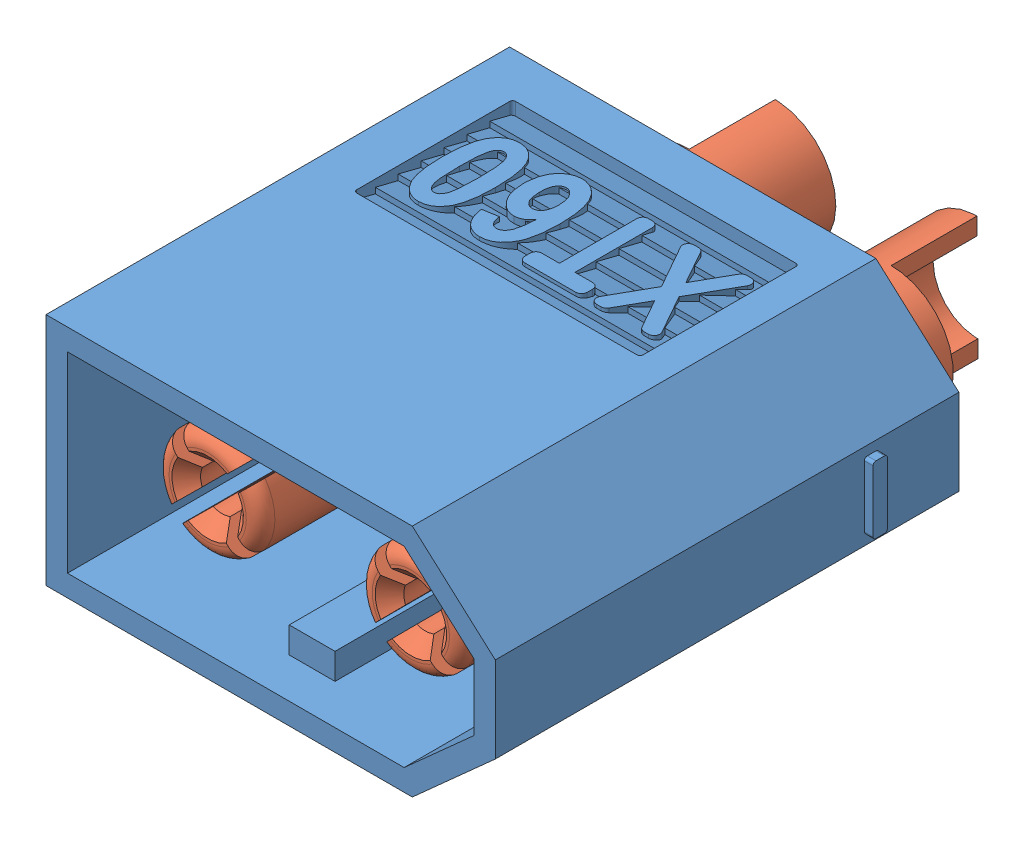
SolidWorks assembly XT-60_Macho, configuration Valor predeterminado. Lengths in mm.
Overall size (16.3 8.2 28.2).
3 component instances, 2 part files, 4 mates.
Components (placement in the parent):
- XT-60_Macho-1: XT-60_Macho [Valor predeterminado] at (-37.9952 28.536 -8.1) size (16.3 8.2 16.2)
- PinoXT-60_Macho-1: PinoXT-60_Macho [Valor predeterminado] at (-26.6452 32.636 -13.1) x (-0.008124 0.999967 0) z (0.999967 0.008124 0) size (4.3 26.83 4.3)
- PinoXT-60_Macho-2: PinoXT-60_Macho [Valor predeterminado] at (-33.7452 32.636 -13.1) x (-0.014321 -0.999897 0) z (-0.999897 0.014321 0) size (4.3 26.83 4.3)
Mates (geometry in assembly coordinates):
- Concêntrico1: concentric aligned: cylinder of XT-60_Macho-1 through (-26.6452 32.636 8.1) axis (0 0 -1) radius 2.15; cylinder of PinoXT-60_Macho-1 through (-26.6452 32.636 -3.1) axis (0 0 -1) radius 2.15
- Concêntrico2: concentric aligned: cylinder of XT-60_Macho-1 through (-33.7452 32.636 8.1) axis (0 0 -1) radius 2.15; cylinder of PinoXT-60_Macho-2 through (-33.7452 32.636 -3.1) axis (0 0 -1) radius 2.15
- Distância1: distance = 1.4 mm aligned: plane of PinoXT-60_Macho-1 through (-26.6627 34.786 6.7) normal (0 0 1); plane of XT-60_Macho-1 through (-37.9952 28.536 8.1) normal (0 0 1)
- Distância2: distance = 1.4 mm aligned: plane of PinoXT-60_Macho-2 through (-33.776 30.4863 6.7) normal (0 0 1); plane of XT-60_Macho-1 through (-37.9952 28.536 8.1) normal (0 0 1)
